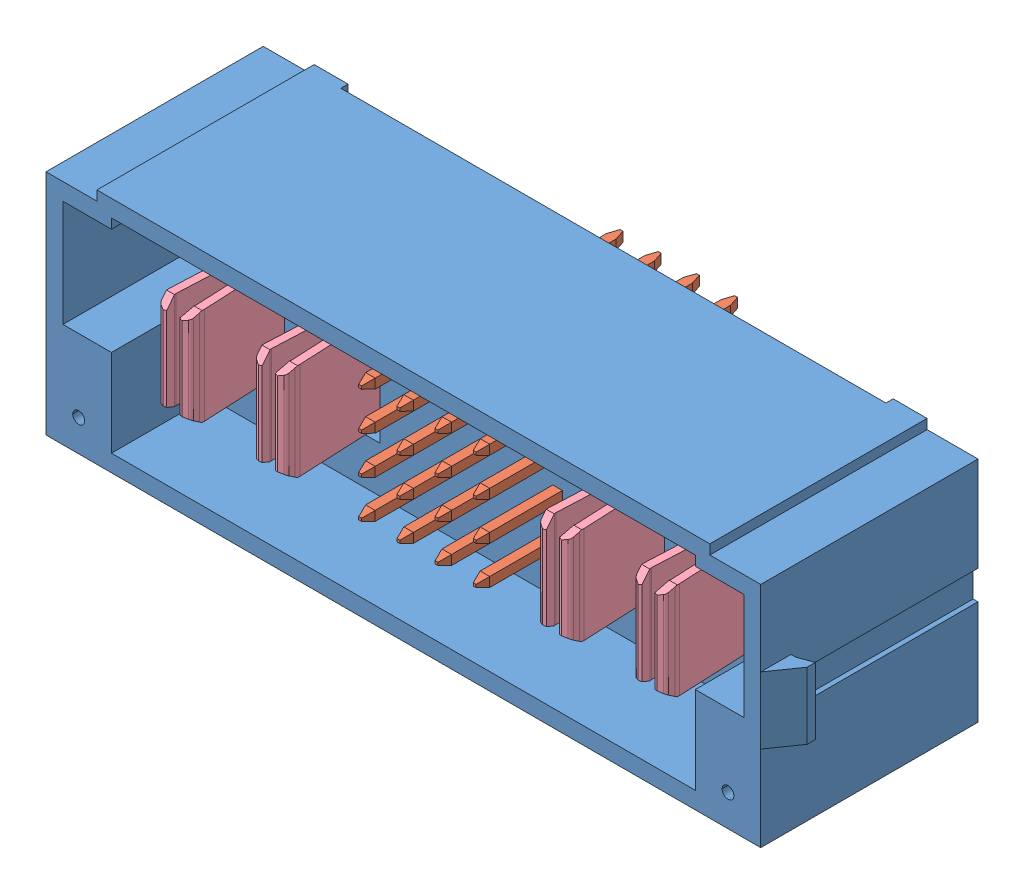
SolidWorks assembly MPTC_02_16_02_6_30_01_L_V_LC, configuration Default. Lengths in mm.
Overall size (39.44 12.45 14.43).
8 component instances, 4 part files, 0 mates.
Components (placement in the parent):
- _MPTC_02_16_02_6_30_V_LC_t_2-1: _MPTC_02_16_02_6_30_V_LC_t_2 [Default] at origin size (39.44 12.45 11.38)
- _MPTC_02_16_02_6_30_01_V_p_4-1: _MPTC_02_16_02_6_30_01_V_p_4 [Default] at (0 0.0048 0.532) size (6.5 6.5 13.69)
- _MPTC_01_04_01_6_30_01_L_V_c_6-1: _MPTC_01_04_01_6_30_01_L_V_c_6 [Default] at (16.255 -2.145 -4.76) x (0 1 0) z (1 0 0) size (1.42 4.7 0.25)
- _MPTC_01_04_01_6_30_01_L_V_c_6-2: _MPTC_01_04_01_6_30_01_L_V_c_6 [Default] at (-16.255 -2.145 -4.76) x (0 1 0) z (1 0 0) size (1.42 4.7 0.25)
- _MPTC_01_V_pp_9-1: _MPTC_01_V_pp_9 [Default] at (12.445 -2.605 -1.744) x (0 0 1) z (-1 0 0) size (13.75 7.62 2.29)
- _MPTC_01_V_pp_9-2: _MPTC_01_V_pp_9 [Default] at (-12.445 -2.605 -1.744) x (0 0 1) z (-1 0 0) size (13.75 7.62 2.29)
- _MPTC_01_V_pp_9-3: _MPTC_01_V_pp_9 [Default] at (7.445 -2.605 -1.744) x (0 0 1) z (-1 0 0) size (13.75 7.62 2.29)
- _MPTC_01_V_pp_9-4: _MPTC_01_V_pp_9 [Default] at (-7.445 -2.605 -1.744) x (0 0 1) z (-1 0 0) size (13.75 7.62 2.29)
